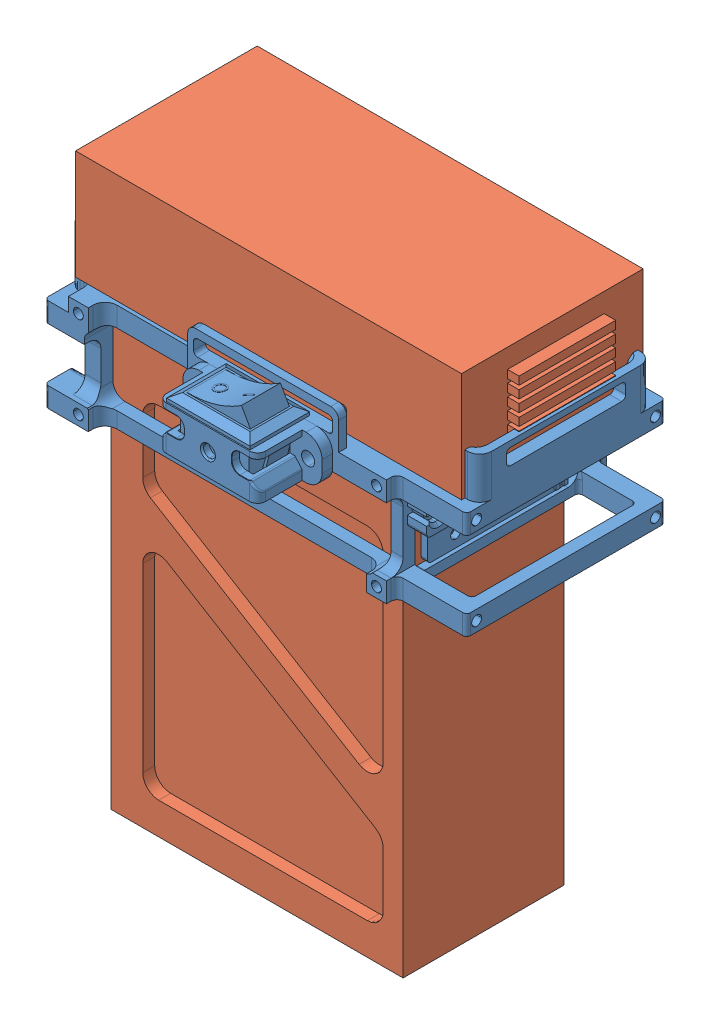
SolidWorks assembly 电池, configuration 默认. Lengths in mm.
Overall size (104.8 141.62 69.31).
2 component instances, 2 part files, 3 mates.
Components (placement in the parent):
- RoboMaster 电池架.step-1: RoboMaster 电池架.step [默认] at (-44.234 7.5299 96.5464) size (103.5 37.5 69.31)
- 电池.step-1: 电池.step [默认] at (32.266 -106.5901 116.5464) x (-1 0 0) z (0 0 -1) size (104 141.62 45.7)
Mates (geometry in assembly coordinates):
- 重合3: coincident anti-aligned: plane of RoboMaster 电池架.step-1 through (-41.234 -22.1713 121.1476) normal (1 0 0); plane of 电池.step-1 through (-41.234 7.5299 116.5464) normal (-1 0 0)
- 重合4: coincident anti-aligned: plane of RoboMaster 电池架.step-1 through (-50.0352 -22.1713 76.0464) normal (0 0 1); plane of 电池.step-1 through (32.266 7.5299 76.0464) normal (0 0 -1)
- 重合5: coincident anti-aligned: plane of RoboMaster 电池架.step-1 through (-53.3352 7.5299 64.7452) normal (0 1 0); plane of 电池.step-1 through (32.266 7.5299 116.5464) normal (0 -1 0)
